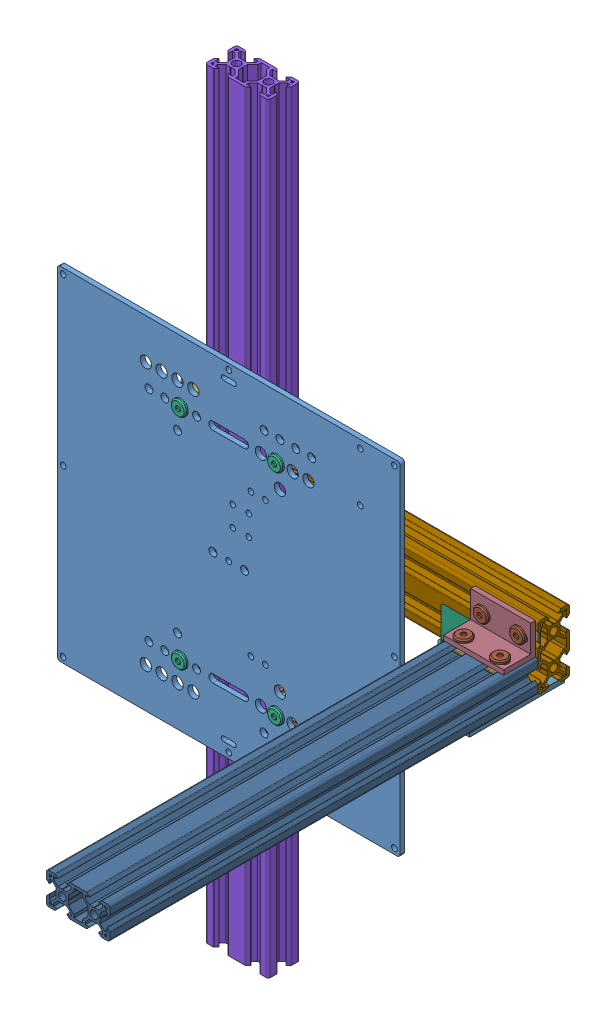
SolidWorks assembly V-Slot Machine 1, configuration Default. Lengths in mm.
Overall size (278 480 290).
74 component instances, 15 part files, 34 mates.
Components (placement in the parent):
- V-Slot Universal Build Plate-1: V-Slot Universal Build Plate [Default] at (-87.6926 -19.3503 62.1637) size (216 216 3)
- V-Slot Delrin Dual Wheel Assembly-1: V-Slot Delrin Dual Wheel Assembly [Default] at (-107.703 40.593 59.8984) x (0.400013 0.91651 0) z (0 0 1) size (23.89 23.89 27.2)
  - Delrin Dual V-Wheel-1: Delrin Dual V-Wheel [Default] at (4.1766 13.0717 -11.0846) size (23.89 23.89 10.23)
  - Precision Ball Bearing-1: Precision Ball Bearing [Default] at (4.1766 13.0717 -8.0846) x (0 0 -1) z (1 0 0) size (5 16 16)
  - Precision Ball Bearing-2: Precision Ball Bearing [Default] at (4.1766 13.0717 -14.0846) x (0 0 -1) z (1 0 0) size (5 16 16)
  - 5mm Precision Washer-1: 5mm Precision Washer [Default] at (4.1766 13.0717 -11.5846) x (0 0 1) z (-1 0 0) size (1 10 10)
  - .25 Inch Aluminum Spacer-1: .25 Inch Aluminum Spacer [Default] at (4.1766 13.0717 0.7654) x (0 0 -1) z (1 0 0) size (6.35 8 8)
  - 5mm Low Profile Socket Head Screw - Multiple Lengths-1: 5mm Low Profile Socket Head Screw - Multiple Lengths [Default] at (4.1766 13.0717 5.5154) x (0 0 -1) z (1 0 0) size (27.2 9.5 9.5)
  - Nylon Insert Hex Locknut 5mm-1: Nylon Insert Hex Locknut 5mm [Default] at (4.1766 13.0717 -16.5846) x (-0.923728 -0.383049 0) z (0 0 -1) size (7.68 8.82 4.5)
- V-Slot Delrin Dual Wheel Assembly-2: V-Slot Delrin Dual Wheel Assembly [Default] at (-122.1892 -101.422 59.8984) size (23.89 23.89 27.2)
  - Delrin Dual V-Wheel-1: Delrin Dual V-Wheel [Default] at (4.1766 13.0717 -11.0846) size (23.89 23.89 10.23)
  - Precision Ball Bearing-1: Precision Ball Bearing [Default] at (4.1766 13.0717 -8.0846) x (0 0 -1) z (1 0 0) size (5 16 16)
  - Precision Ball Bearing-2: Precision Ball Bearing [Default] at (4.1766 13.0717 -14.0846) x (0 0 -1) z (1 0 0) size (5 16 16)
  - 5mm Precision Washer-1: 5mm Precision Washer [Default] at (4.1766 13.0717 -11.5846) x (0 0 1) z (-1 0 0) size (1 10 10)
  - .25 Inch Aluminum Spacer-1: .25 Inch Aluminum Spacer [Default] at (4.1766 13.0717 0.7654) x (0 0 -1) z (1 0 0) size (6.35 8 8)
  - 5mm Low Profile Socket Head Screw - Multiple Lengths-1: 5mm Low Profile Socket Head Screw - Multiple Lengths [Default] at (4.1766 13.0717 5.5154) x (0 0 -1) z (1 0 0) size (27.2 9.5 9.5)
  - Nylon Insert Hex Locknut 5mm-1: Nylon Insert Hex Locknut 5mm [Default] at (4.1766 13.0717 -16.5846) x (-0.923728 -0.383049 0) z (0 0 -1) size (7.68 8.82 4.5)
- V-Slot Delrin Dual Wheel Assembly-3: V-Slot Delrin Dual Wheel Assembly [Default] at (-49.8344 38.1829 59.8984) x (0.62878 0.777583 0) z (0 0 1) size (23.89 23.89 27.2)
  - Delrin Dual V-Wheel-1: Delrin Dual V-Wheel [Default] at (4.1766 13.0717 -11.0846) size (23.89 23.89 10.23)
  - Precision Ball Bearing-1: Precision Ball Bearing [Default] at (4.1766 13.0717 -8.0846) x (0 0 -1) z (1 0 0) size (5 16 16)
  - Precision Ball Bearing-2: Precision Ball Bearing [Default] at (4.1766 13.0717 -14.0846) x (0 0 -1) z (1 0 0) size (5 16 16)
  - 5mm Precision Washer-1: 5mm Precision Washer [Default] at (4.1766 13.0717 -11.5846) x (0 0 1) z (-1 0 0) size (1 10 10)
  - .25 Inch Aluminum Spacer-1: .25 Inch Aluminum Spacer [Default] at (4.1766 13.0717 0.7654) x (0 0 -1) z (1 0 0) size (6.35 8 8)
  - 5mm Low Profile Socket Head Screw - Multiple Lengths-1: 5mm Low Profile Socket Head Screw - Multiple Lengths [Default] at (4.1766 13.0717 5.5154) x (0 0 -1) z (1 0 0) size (27.2 9.5 9.5)
  - Nylon Insert Hex Locknut 5mm-1: Nylon Insert Hex Locknut 5mm [Default] at (4.1766 13.0717 -16.5846) x (-0.923728 -0.383049 0) z (0 0 -1) size (7.68 8.82 4.5)
- V-Slot Delrin Dual Wheel Assembly-4: V-Slot Delrin Dual Wheel Assembly [Default] at (-61.5492 -101.422 59.8984) size (23.89 23.89 27.2)
  - Delrin Dual V-Wheel-1: Delrin Dual V-Wheel [Default] at (4.1766 13.0717 -11.0846) size (23.89 23.89 10.23)
  - Precision Ball Bearing-1: Precision Ball Bearing [Default] at (4.1766 13.0717 -8.0846) x (0 0 -1) z (1 0 0) size (5 16 16)
  - Precision Ball Bearing-2: Precision Ball Bearing [Default] at (4.1766 13.0717 -14.0846) x (0 0 -1) z (1 0 0) size (5 16 16)
  - 5mm Precision Washer-1: 5mm Precision Washer [Default] at (4.1766 13.0717 -11.5846) x (0 0 1) z (-1 0 0) size (1 10 10)
  - .25 Inch Aluminum Spacer-1: .25 Inch Aluminum Spacer [Default] at (4.1766 13.0717 0.7654) x (0 0 -1) z (1 0 0) size (6.35 8 8)
  - 5mm Low Profile Socket Head Screw - Multiple Lengths-1: 5mm Low Profile Socket Head Screw - Multiple Lengths [Default] at (4.1766 13.0717 5.5154) x (0 0 -1) z (1 0 0) size (27.2 9.5 9.5)
  - Nylon Insert Hex Locknut 5mm-1: Nylon Insert Hex Locknut 5mm [Default] at (4.1766 13.0717 -16.5846) x (-0.923728 -0.383049 0) z (0 0 -1) size (7.68 8.82 4.5)
- 20mm x 40mm x 560mm Extrusion-1: 20mm x 40mm x 560mm Extrusion [Default<As Machined>] at (-87.6926 -240 48.6637) x (0 1 0) z (-1 0 0) size (480 20 40)
- 20mm x 40mm x170mm Extrusion-1: 20mm x 40mm x170mm Extrusion [Default<As Machined>] at (-107.6927 0 28.6637) x (1 0 0) z (0 -1 0) size (190 20 40)
- 20mm x 40mm x270mm Extrusion-1: 20mm x 40mm x270mm Extrusion [Default<As Machined>] at (62.3073 -10.0001 308.6637) x (0 0 -1) z (1 0.000005 0) size (270 20 40)
- Double Universal L-Bracket with Bolts and Tee Nuts-1: Double Universal L-Bracket with Bolts and Tee Nuts [Default] at (53.1163 -3.3335 -17.2597) x (0 0 -1) z (1 0.000005 0) size (25.35 25.35 38)
  - 5mm x 8mm Bolt with Tee Nut-1: 5mm x 8mm Bolt with Tee Nut [Default] at (-25.8297 5.7639 9.7141) size (10.1 10 15)
    - 5mm x 8mm Low Profile Socket Head Screw-1: 5mm x 8mm Low Profile Socket Head Screw [5mm x 8mm Low Profile] at (-34.8438 7.7195 10.4769) size (10.1 9.5 9.5)
    - Tee nut-1: Tee nut [Default] at (-28.2938 2.7205 17.9769) x (0 0 -1) z (1 0 0) size (15 10 3.3)
  - Universal L Bracket - Double-1: Universal L Bracket - Double [Default] at (-55.9235 3.3334 -10.3091) x (0 0 -1) z (1 0 0) size (38 20 20)
  - 5mm x 8mm Bolt with Tee Nut-2: 5mm x 8mm Bolt with Tee Nut [Default] at (-78.493 -26.7604 9.7141) x (0 -1 0) z (0 0 1) size (10.1 10 15)
    - 5mm x 8mm Low Profile Socket Head Screw-1: 5mm x 8mm Low Profile Socket Head Screw [5mm x 8mm Low Profile] at (-34.8438 7.7195 10.4769) size (10.1 9.5 9.5)
    - Tee nut-1: Tee nut [Default] at (-28.2938 2.7205 17.9769) x (0 0 -1) z (1 0 0) size (15 10 3.3)
  - 5mm x 8mm Bolt with Tee Nut-3: 5mm x 8mm Bolt with Tee Nut [Default] at (-78.493 -26.7604 -13.2859) x (0 -1 0) z (0 0 1) size (10.1 10 15)
    - 5mm x 8mm Low Profile Socket Head Screw-1: 5mm x 8mm Low Profile Socket Head Screw [5mm x 8mm Low Profile] at (-34.8438 7.7195 10.4769) size (10.1 9.5 9.5)
    - Tee nut-1: Tee nut [Default] at (-28.2938 2.7205 17.9769) x (0 0 -1) z (1 0 0) size (15 10 3.3)
  - 5mm x 8mm Bolt with Tee Nut-4: 5mm x 8mm Bolt with Tee Nut [Default] at (-25.8297 5.4639 -13.2859) size (10.1 10 15)
    - 5mm x 8mm Low Profile Socket Head Screw-1: 5mm x 8mm Low Profile Socket Head Screw [5mm x 8mm Low Profile] at (-34.8438 7.7195 10.4769) size (10.1 9.5 9.5)
    - Tee nut-1: Tee nut [Default] at (-28.2938 2.7205 17.9769) x (0 0 -1) z (1 0 0) size (15 10 3.3)
- 5 Hole 90 Degree Bracket with Bolts-1: 5 Hole 90 Degree Bracket with Bolts [Default] at (96.8131 42.9876 15.9002) x (0 0 1) z (0.000005 -1 0) size (60 60 10.1)
  - 5 Hole 90 Degree Joining Plate-1: 5 Hole 90 Degree Joining Plate [Default] at (4.3285 16.0061 65.9875) size (60 60 3)
  - 5mm x 8mm Bolt with Tee Nut-1: 5mm x 8mm Bolt with Tee Nut [Default] at (3.8516 58.2866 32.8937) x (0 0 -1) z (1 0 0) size (10.1 10 15)
    - 5mm x 8mm Low Profile Socket Head Screw-1: 5mm x 8mm Low Profile Socket Head Screw [5mm x 8mm Low Profile] at (-34.8438 7.7195 10.4769) size (10.1 9.5 9.5)
    - Tee nut-1: Tee nut [Default] at (-28.2938 2.7205 17.9769) x (0 0 -1) z (1 0 0) size (15 10 3.3)
  - 5mm x 8mm Bolt with Tee Nut-2: 5mm x 8mm Bolt with Tee Nut [Default] at (3.8516 38.2866 32.8937) x (0 0 -1) z (1 0 0) size (10.1 10 15)
    - 5mm x 8mm Low Profile Socket Head Screw-1: 5mm x 8mm Low Profile Socket Head Screw [5mm x 8mm Low Profile] at (-34.8438 7.7195 10.4769) size (10.1 9.5 9.5)
    - Tee nut-1: Tee nut [Default] at (-28.2938 2.7205 17.9769) x (0 0 -1) z (1 0 0) size (15 10 3.3)
  - 5mm x 8mm Bolt with Tee Nut-3: 5mm x 8mm Bolt with Tee Nut [Default] at (3.8516 18.2866 32.8937) x (0 0 -1) z (1 0 0) size (10.1 10 15)
    - 5mm x 8mm Low Profile Socket Head Screw-1: 5mm x 8mm Low Profile Socket Head Screw [5mm x 8mm Low Profile] at (-34.8438 7.7195 10.4769) size (10.1 9.5 9.5)
    - Tee nut-1: Tee nut [Default] at (-28.2938 2.7205 17.9769) x (0 0 -1) z (1 0 0) size (15 10 3.3)
  - 5mm x 8mm Bolt with Tee Nut-4: 5mm x 8mm Bolt with Tee Nut [Default] at (42.048 15.5292 32.8937) x (0 0 -1) z (0 1 0) size (10.1 10 15)
    - 5mm x 8mm Low Profile Socket Head Screw-1: 5mm x 8mm Low Profile Socket Head Screw [5mm x 8mm Low Profile] at (-34.8438 7.7195 10.4769) size (10.1 9.5 9.5)
    - Tee nut-1: Tee nut [Default] at (-28.2938 2.7205 17.9769) x (0 0 -1) z (1 0 0) size (15 10 3.3)
  - 5mm x 8mm Bolt with Tee Nut-5: 5mm x 8mm Bolt with Tee Nut [Default] at (62.048 15.5292 32.8937) x (0 0 -1) z (0 1 0) size (10.1 10 15)
    - 5mm x 8mm Low Profile Socket Head Screw-1: 5mm x 8mm Low Profile Socket Head Screw [5mm x 8mm Low Profile] at (-34.8438 7.7195 10.4769) size (10.1 9.5 9.5)
    - Tee nut-1: Tee nut [Default] at (-28.2938 2.7205 17.9769) x (0 0 -1) z (1 0 0) size (15 10 3.3)
- corner_connector_90deg-1: corner_connector_90deg [Défaut] at (42.3073 -10.1301 38.6637) x (0.000011 -1 0) z (0 0 -1) size (20 20 20)
- 5mm x 8mm Bolt with Tee Nut-1: 5mm x 8mm Bolt with Tee Nut [Default] at (71.9009 0.3471 40.9442) x (1 0.000011 0) z (0.000011 -1 0) size (10.1 10 15)
  - 5mm x 8mm Low Profile Socket Head Screw-1: 5mm x 8mm Low Profile Socket Head Screw [5mm x 8mm Low Profile] at (-34.8438 7.7195 10.4769) size (10.1 9.5 9.5)
  - Tee nut-1: Tee nut [Default] at (-28.2938 2.7205 17.9769) x (0 0 -1) z (1 0 0) size (15 10 3.3)
- 5mm x 8mm Bolt with Tee Nut-2: 5mm x 8mm Bolt with Tee Nut [Default] at (24.5876 0.3466 9.07) x (0 0 -1) z (0.000011 -1 0) size (10.1 10 15)
  - 5mm x 8mm Low Profile Socket Head Screw-1: 5mm x 8mm Low Profile Socket Head Screw [5mm x 8mm Low Profile] at (-34.8438 7.7195 10.4769) size (10.1 9.5 9.5)
  - Tee nut-1: Tee nut [Default] at (-28.2938 2.7205 17.9769) x (0 0 -1) z (1 0 0) size (15 10 3.3)
Mates (geometry in assembly coordinates):
- Coincident1: coincident anti-aligned: plane of V-Slot Universal Build Plate-1 through (-193.9426 -125.6003 63.6637) normal (0 0 1); plane of V-Slot Delrin Dual Wheel Assembly-3/5mm Low Profile Socket Head Screw - Multiple Lengths-1 through (-59.3166 51.2217 63.6637) normal (0 0 -1)
- Coincident2: coincident anti-aligned: plane of V-Slot Universal Build Plate-1 through (-193.9426 -125.6003 63.6637) normal (0 0 1); plane of V-Slot Delrin Dual Wheel Assembly-4/5mm Low Profile Socket Head Screw - Multiple Lengths-1 through (-57.3726 -85.8503 63.6637) normal (0 0 -1)
- Coincident3: coincident anti-aligned: plane of V-Slot Universal Build Plate-1 through (-193.9426 -125.6003 63.6637) normal (0 0 1); plane of V-Slot Delrin Dual Wheel Assembly-1/5mm Low Profile Socket Head Screw - Multiple Lengths-1 through (-120.3039 50.6498 63.6637) normal (0 0 -1)
- Coincident4: coincident anti-aligned: plane of V-Slot Universal Build Plate-1 through (-193.9426 -125.6003 63.6637) normal (0 0 1); plane of V-Slot Delrin Dual Wheel Assembly-2/5mm Low Profile Socket Head Screw - Multiple Lengths-1 through (-118.0126 -85.8503 63.6637) normal (0 0 -1)
- Concentric3: concentric anti-aligned: cylinder of V-Slot Universal Build Plate-1 through (-118.0126 -88.3503 63.6637) axis (0 0 -1) radius 2.5; cylinder of V-Slot Delrin Dual Wheel Assembly-2/.25 Inch Aluminum Spacer-1 through (-118.0126 -88.3503 54.3137) axis (0 0 1) radius 4
- Concentric4: concentric anti-aligned: cylinder of V-Slot Universal Build Plate-1 through (-118.0126 49.6497 63.6637) axis (0 0 -1) radius 2.5; cylinder of V-Slot Delrin Dual Wheel Assembly-1/.25 Inch Aluminum Spacer-1 through (-118.0126 49.6497 54.3137) axis (0 0 1) radius 4
- Concentric5: concentric anti-aligned: cylinder of V-Slot Universal Build Plate-1 through (-57.3726 49.6497 63.6637) axis (0 0 -1) radius 3.57; cylinder of V-Slot Delrin Dual Wheel Assembly-3/.25 Inch Aluminum Spacer-1 through (-57.3726 49.6497 54.3137) axis (0 0 1) radius 4
- Coincident6: coincident: line of 20mm x 40mm x 560mm Extrusion-1 through (-87.6926 -240 48.6637) axis (0 1 0); plane of assembly
- Coincident7: coincident: line of 20mm x 40mm x170mm Extrusion-1 through (-107.6927 0 28.6637) axis (1 0 0); plane of assembly
- Coincident13: coincident: plane of 20mm x 40mm x 560mm Extrusion-1 through (-107.6926 240 57.1638) normal (-1 0 0.000005); point of 20mm x 40mm x170mm Extrusion-1
- Coincident14: coincident anti-aligned: plane of 20mm x 40mm x 560mm Extrusion-1 through (-92.7926 240 38.6637) normal (0 0 -1); plane of 20mm x 40mm x170mm Extrusion-1 through (82.3073 -5.1 38.6637) normal (0 0 1)
- Coincident17: coincident aligned: plane of 20mm x 40mm x170mm Extrusion-1 through (82.3073 14.9 19.4495) normal (1 0 0); plane of 20mm x 40mm x270mm Extrusion-1 through (82.3073 -18.5 38.6637) normal (1 0 0)
- Coincident18: coincident: point of 20mm x 40mm x170mm Extrusion-1; point of 20mm x 40mm x270mm Extrusion-1
- Coincident20: coincident: moEndPointRef_w of 20mm x 40mm x 560mm Extrusion-1; plane of assembly
- Coincident21: coincident anti-aligned: plane of 20mm x 40mm x 560mm Extrusion-1 through (-92.7926 240 58.6637) normal (0 0 1); plane of assembly through (0 0 58.6637) normal (0 0 -1)
- Concentric6: concentric anti-aligned: cylinder of V-Slot Universal Build Plate-1 through (-57.3726 -88.3503 63.6637) axis (0 0 -1) radius 3.57; cylinder of V-Slot Delrin Dual Wheel Assembly-4/.25 Inch Aluminum Spacer-1 through (-57.3726 -88.3503 54.3137) axis (0 0 1) radius 4
- Parallel5: parallel anti-aligned: plane of V-Slot Universal Build Plate-1 through (-193.9426 -125.6003 63.6637) normal (0 0 1); plane of assembly through (0 0 60.6637) normal (0 0 -1)
- Coincident26: coincident: plane of V-Slot Universal Build Plate-1 through (-67.6926 17.9211 62.1637) normal (1 0 0); line of 20mm x 40mm x 560mm Extrusion-1 through (-67.6926 -280 48.6637) axis (0 1 0)
- LimitDistance2: limit distance = 154.0789 mm: plane of V-Slot Universal Build Plate-1 through (-173.9426 125.9211 63.6637) normal (0 1 0); plane of 20mm x 40mm x 560mm Extrusion-1 through (-52.7926 280 57.878) normal (0 1 0)
- Coincident29: coincident: plane of 20mm x 40mm x170mm Extrusion-1 through (82.3073 -5.1 38.6637) normal (0 0 1); plane of Double Universal L-Bracket with Bolts and Tee Nuts-1/Universal L Bracket - Double-1 through (80.8071 20 38.6637) normal (0 0 -1)
- Coincident30: coincident: plane of 20mm x 40mm x270mm Extrusion-1 through (67.4072 0 38.6637) normal (-0.000005 1 0); plane of Double Universal L-Bracket with Bolts and Tee Nuts-1/Universal L Bracket - Double-1 through (80.8072 0 38.6637) normal (0.000005 -1 0)
- Coincident31: coincident: line of 20mm x 40mm x270mm Extrusion-1 through (80.8072 0 38.6637) axis (0 0 1); line of Double Universal L-Bracket with Bolts and Tee Nuts-1/Universal L Bracket - Double-1 through (80.8072 0 38.6637) axis (0 0 1)
- Coincident35: coincident: plane of 20mm x 40mm x270mm Extrusion-1 through (67.4073 -20 38.6637) normal (0.000005 -1 0); plane of 5 Hole 90 Degree Bracket with Bolts-1/5 Hole 90 Degree Joining Plate-1 through (80.8073 -20 20.2287) normal (-0.000005 1 0)
- Coincident36: coincident: line of 20mm x 40mm x270mm Extrusion-1 through (80.8073 -20 38.6637) axis (0 0 1); line of 5 Hole 90 Degree Bracket with Bolts-1/5 Hole 90 Degree Joining Plate-1 through (80.8073 -20 20.2287) axis (0 0 1)
- Coincident44: coincident: plane of 20mm x 40mm x170mm Extrusion-1 through (82.3073 -14.9 38.6637) normal (0 0 1); plane of corner_connector_90deg-1 through (42.3074 -20.1301 38.6637) normal (0 0 -1)
- Coincident45: coincident: plane of 20mm x 40mm x270mm Extrusion-1 through (42.3074 -18.5002 38.6637) normal (-1 -0.000011 0); plane of corner_connector_90deg-1 through (42.3074 -20.1301 58.6637) normal (1 0.000011 0)
- Parallel10: parallel: plane of corner_connector_90deg-1 through (42.3072 -0.1301 58.6637) normal (-0.000011 1 0); plane of 5mm x 8mm Bolt with Tee Nut-2/Tee nut-1 through (27.3083 -17.6302 35.7137) normal (0.000011 -1 0)
- Parallel11: parallel: plane of corner_connector_90deg-1 through (42.3072 -0.1301 58.6637) normal (-0.000011 1 0); plane of 5mm x 8mm Bolt with Tee Nut-1/Tee nut-1 through (45.2573 -17.63 43.6647) normal (0.000011 -1 0)
- Concentric8: concentric: cylinder of corner_connector_90deg-1 through (22.3073 -10.1303 48.6637) axis (1 0.000011 0) radius 3.57; cylinder of 5mm x 8mm Bolt with Tee Nut-1/Tee nut-1 through (41.9573 -10.1301 48.6637) axis (1 0.000011 0) radius 2.6
- Coincident52: coincident: plane of corner_connector_90deg-1 through (38.8074 -20.1301 58.6637) normal (-1 -0.000011 0); plane of 5mm x 8mm Bolt with Tee Nut-1/5mm x 8mm Low Profile Socket Head Screw-1 through (38.8073 -10.1301 51.1637) normal (1 0.000011 0)
- Coincident53: coincident: plane of corner_connector_90deg-1 through (42.3074 -20.1301 42.1637) normal (0 0 1); plane of 5mm x 8mm Bolt with Tee Nut-2/5mm x 8mm Low Profile Socket Head Screw-1 through (34.8073 -10.1302 42.1637) normal (0 0 -1)
- Concentric9: concentric: cylinder of corner_connector_90deg-1 through (32.3073 -10.1302 58.6637) axis (0 0 -1) radius 3.57; cylinder of 5mm x 8mm Bolt with Tee Nut-2/Tee nut-1 through (32.3073 -10.1302 39.0137) axis (0 0 -1) radius 2.6
- Coincident54: coincident anti-aligned: plane of V-Slot Universal Build Plate-1 through (-87.6926 -19.3503 62.1637) normal (1 0 0); plane of 20mm x 40mm x 560mm Extrusion-1 through (-87.6926 -240 48.6637) normal (-1 0 0)
- LimitDistance3: limit distance = 151.3503 mm aligned: plane of V-Slot Universal Build Plate-1 through (-193.9426 88.6497 63.6637) normal (0 1 0); plane of 20mm x 40mm x 560mm Extrusion-1 through (-72.7926 240 57.878) normal (0 1 0)
